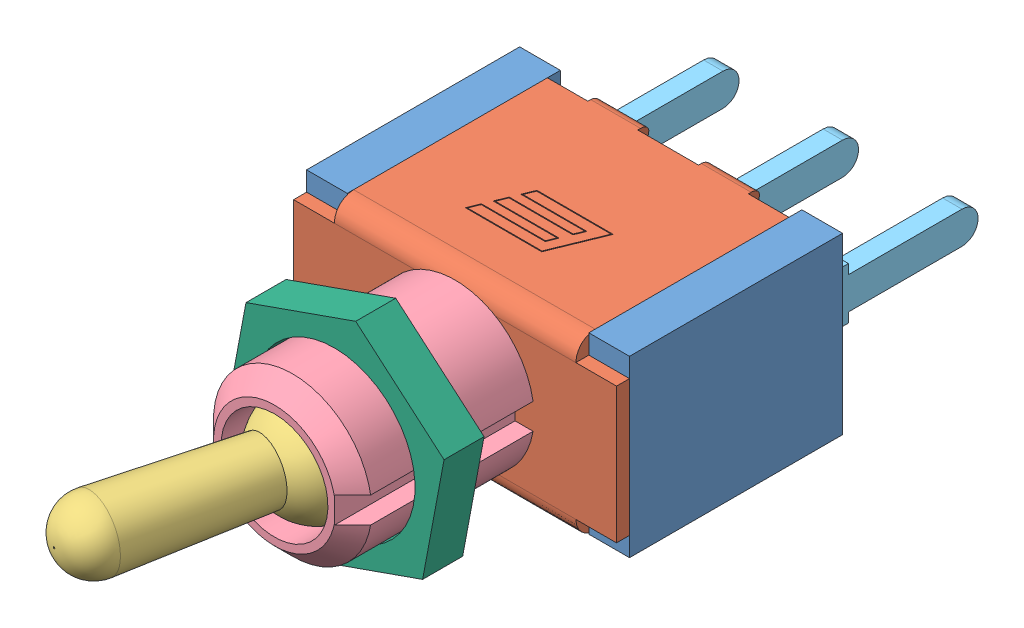
SolidWorks assembly 100SP3T2B3M2RE - TOGGLE, MICRO, 3 POS, .250 THD BUSHING, SHORT BAT, configuration Default. Lengths in mm.
Overall size (12.7 12.2 29.84).
6 component instances, 6 part files, 2 mates.
Components (placement in the parent):
- 100 SP Housing-1: 100 SP Housing [Default] at origin size (12.7 6.86 8.38)
- 100 SP Top Bracket-1: 100 SP Top Bracket [Default] at (0 0 4.445) x (1 0 0) z (0 1 0) size (12.7 8.89 6.86)
- 100 T2-1: 100 T2 [Default] at (0 0 14.32) x (0 -1 0) z (-0.21644 0 0.976296) size (4.2 4.2 10.77)
- 100 B3 Bushing-1: 100 B3 Bushing [Default] x (-1 0 0) z (0 0 1) size (6.18 6.22 7.1)
- 100 SP M2 Terminal-1: 100 SP M2 Terminal [Default] x (-1 0 0) z (0 0 -1) size (12.56 4.43 6.6)
- Nut^100SP3T2B3M2RE - TOGGLE, MICRO, 3 POS, .250 THD BUSHING, SHORT BAT-1: Nut^100SP3T2B3M2RE - TOGGLE, MICRO, 3 POS, .250 THD BUSHING, SHORT BAT [Default] at (0 0 12.065) x (0.725286 -0.688448 0) z (0 0 1) size (9.14 8.15 1.57) (virtual)
Mates (geometry in assembly coordinates):
- Concentric1: concentric aligned: cylinder of 100 B3 Bushing-1 through (0 0 8.89) axis (0 0 1) radius 3.11; cylinder of Nut^100SP3T2B3M2RE - TOGGLE, MICRO, 3 POS, .250 THD BUSHING, SHORT BAT-1 through (0 0 12.065) axis (0 0 1) radius 3.175
- Distance1: distance = 3.175 mm anti-aligned: plane of Nut^100SP3T2B3M2RE - TOGGLE, MICRO, 3 POS, .250 THD BUSHING, SHORT BAT-1 through (0 0 12.065) normal (0 0 -1); plane of 100 SP Top Bracket-1 through (0 2.67 8.89) normal (0 0 1)
